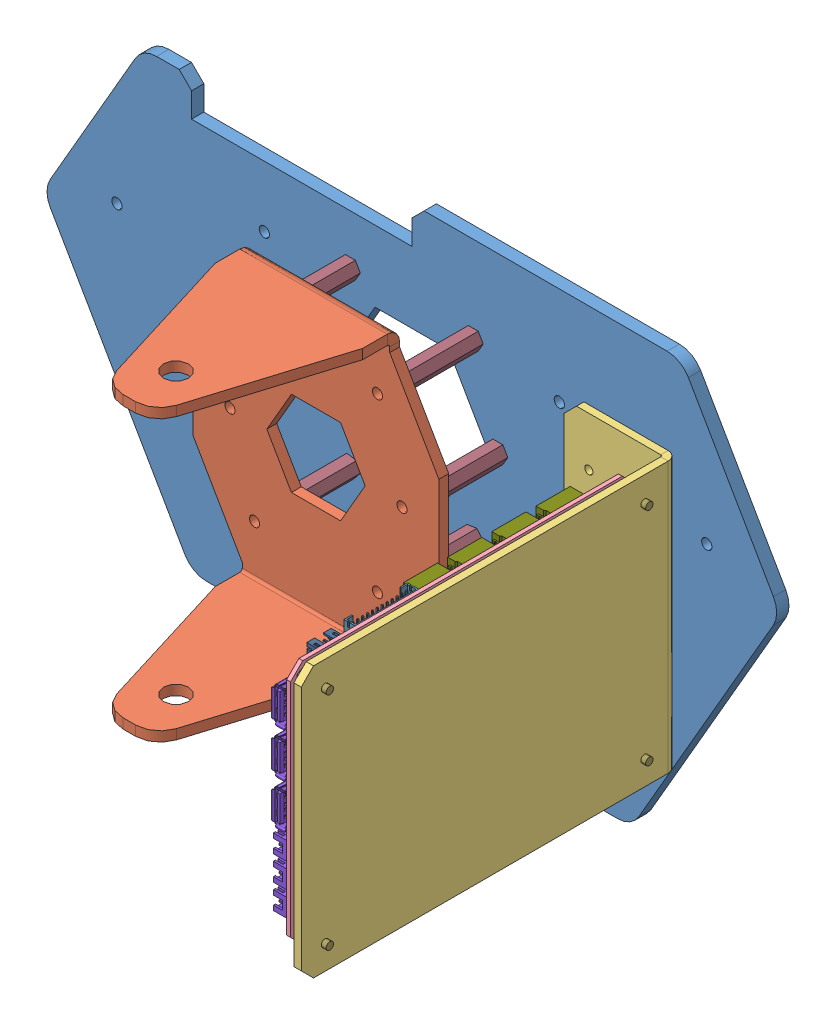
SolidWorks assembly Work Table Assembly, configuration 預設. Lengths in mm.
Overall size (296.91 174.81 163).
95 component instances, 31 part files, 24 mates.
Components (placement in the parent):
- Work Table-1: Work Table [預設] at origin size (296.91 174.81 5)
- Chassis Handle Steel-1: Chassis Handle Steel [Default] at (0 0 41) x (1 0 0) z (0 -1 0) size (100 80 117.92)
- Main Board Mount-1: Main Board Mount [預設] at (105 35.0962 8) x (1 0 0) z (0 -1 0) size (43 153 110)
- Main Board-1: Main Board [預設] at (99 242.1212 -111.1317) x (0 -1 0) z (-1 0 0) size (100 140 20.2)
  - BoardOutline_Main Board-1: BoardOutline_Main Board [預設] at origin size (100 140 1.6)
  - XTAL_ECS-120-32-5P-TR_ECS-120-32-5P-TR_1-1: XTAL_ECS-120-32-5P-TR_ECS-120-32-5P-TR_1 [預設] at (267.025 238.5 1.6) x (0 1 0) z (0 0 1) size (13.2 4.8 4.31)
  - FCI_06-381-2PIN_(180)_2_Pin_1-1: FCI_06-381-2PIN_(180)_2_Pin_1 [預設] at (287.025 139.5 1.6) size (8.81 7.6 12.7)
  - LED_0603_1608_BLUE_LED_1-1: LED_0603_1608_BLUE_LED_1 [預設] at (305 250.5 1.6) size (1.6 0.8 0.53)
  - LED_0603_1608_BLUE_LED_1-2: LED_0603_1608_BLUE_LED_1 [預設] at (305.025 248.5 1.6) size (1.6 0.8 0.53)
  - LED_0603_1608_BLUE_LED_1-3: LED_0603_1608_BLUE_LED_1 [預設] at (305.025 246.5 1.6) size (1.6 0.8 0.53)
  - LED_0603_1608_BLUE_LED_1-4: LED_0603_1608_BLUE_LED_1 [預設] at (305.025 244.5 1.6) size (1.6 0.8 0.53)
  - OST_USB-A1HSW6_USB-A1HSW6_1-1: OST_USB-A1HSW6_USB-A1HSW6_1 [預設] at (229 256.5 1.6) x (-1 0 0) z (0 0 1) size (15.8 14.1 10.8)
  - OST_USB-A1HSW6_USB-A1HSW6_1-2: OST_USB-A1HSW6_USB-A1HSW6_1 [預設] at (247 256.5 1.6) x (-1 0 0) z (0 0 1) size (15.8 14.1 10.8)
  - OST_USB-A1HSW6_USB-A1HSW6_1-3: OST_USB-A1HSW6_USB-A1HSW6_1 [預設] at (265 256.5 1.6) x (-1 0 0) z (0 0 1) size (15.8 14.1 10.8)
  - JST_B3B-PH-K_3_Pin_1-1: JST_B3B-PH-K_3_Pin_1 [預設] at (251 214.5 1.6) size (7.9 4.5 9.4)
  - JST_B3B-PH-K_3_Pin_1-2: JST_B3B-PH-K_3_Pin_1 [預設] at (263 214.5 1.6) size (7.9 4.5 9.4)
  - JST_B3B-PH-K_3_Pin_1-3: JST_B3B-PH-K_3_Pin_1 [預設] at (278.875 207.7 1.6) size (7.9 4.5 9.4)
  - JST_B3B-PH-K_3_Pin_1-4: JST_B3B-PH-K_3_Pin_1 [預設] at (278.875 215.075 1.6) size (7.9 4.5 9.4)
  - JST_B3B-PH-K_3_Pin_1-5: JST_B3B-PH-K_3_Pin_1 [預設] at (253 146.5 1.6) size (7.9 4.5 9.4)
  - JST_B3B-PH-K_3_Pin_1-6: JST_B3B-PH-K_3_Pin_1 [預設] at (238 157.5 1.6) size (7.9 4.5 9.4)
  - JST_B3B-PH-K_3_Pin_1-7: JST_B3B-PH-K_3_Pin_1 [預設] at (253 157.5 1.6) size (7.9 4.5 9.4)
  - JST_B3B-PH-K_3_Pin_1-8: JST_B3B-PH-K_3_Pin_1 [預設] at (245 222.5 1.6) size (7.9 4.5 9.4)
  - JST_B3B-PH-K_3_Pin_1-9: JST_B3B-PH-K_3_Pin_1 [預設] at (257 222.5 1.6) size (7.9 4.5 9.4)
  - JST_B3B-PH-K_3_Pin_1-10: JST_B3B-PH-K_3_Pin_1 [預設] at (238 146.5 1.6) size (7.9 4.5 9.4)
  - JST_B3B-PH-K_3_Pin_1-11: JST_B3B-PH-K_3_Pin_1 [預設] at (226.6878 214.4734 1.6) size (7.9 4.5 9.4)
  - JST_B3B-PH-K_3_Pin_1-12: JST_B3B-PH-K_3_Pin_1 [預設] at (239 214.5 1.6) size (7.9 4.5 9.4)
  - JST_B4B-PH-K_4_Pin_1-1: JST_B4B-PH-K_4_Pin_1 [預設] at (238 195.5 1.6) size (9.9 4.5 9.4)
  - JST_B4B-PH-K_4_Pin_1-2: JST_B4B-PH-K_4_Pin_1 [預設] at (251 195.5 1.6) size (9.9 4.5 9.4)
  - JST_B4B-PH-K_4_Pin_1-3: JST_B4B-PH-K_4_Pin_1 [預設] at (245 166.5 1.6) size (9.9 4.5 9.4)
  - JST_B4B-PH-K_4_Pin_1-4: JST_B4B-PH-K_4_Pin_1 [預設] at (215.725 245.3 1.6) x (0 1 0) z (0 0 1) size (9.9 4.5 9.4)
  - JST_XH_B6B-XH-A_6_Pin_1-1: JST_XH_B6B-XH-A_6_Pin_1 [預設] at (245 175.5 1.6) size (17.4 5.75 10.4)
  - JST_XH_B6B-XH-A_6_Pin_1-2: JST_XH_B6B-XH-A_6_Pin_1 [預設] at (245 186.5 1.6) size (17.4 5.75 10.4)
  - RES_0603_1608_RF_Resistor_1-1: RES_0603_1608_RF_Resistor_1 [預設] at (301 250.5 1.6) x (-1 0 0) z (0 0 1) size (1.6 0.8 0.45)
  - RES_0603_1608_RF_Resistor_1-2: RES_0603_1608_RF_Resistor_1 [預設] at (249.525 239.5 1.6) x (0 1 0) z (0 0 1) size (1.6 0.8 0.45)
  - RES_0603_1608_RF_Resistor_1-3: RES_0603_1608_RF_Resistor_1 [預設] at (225.85 227.775 1.6) size (1.6 0.8 0.45)
  - RES_0603_1608_RF_Resistor_1-4: RES_0603_1608_RF_Resistor_1 [預設] at (232.15 227.8 1.6) size (1.6 0.8 0.45)
  - RES_0603_1608_RF_Resistor_1-5: RES_0603_1608_RF_Resistor_1 [預設] at (233.725 235.15 1.6) x (0 1 0) z (0 0 1) size (1.6 0.8 0.45)
  - RES_0603_1608_RF_Resistor_1-6: RES_0603_1608_RF_Resistor_1 [預設] at (223.725 235.15 1.6) x (0 1 0) z (0 0 1) size (1.6 0.8 0.45)
  - RES_0603_1608_RF_Resistor_1-7: RES_0603_1608_RF_Resistor_1 [預設] at (238.225 231.65 1.6) x (0 -1 0) z (0 0 1) size (1.6 0.8 0.45)
  - RES_0603_1608_RF_Resistor_1-8: RES_0603_1608_RF_Resistor_1 [預設] at (228.225 231.65 1.6) x (0 -1 0) z (0 0 1) size (1.6 0.8 0.45)
  - RES_0603_1608_RF_Resistor_1-9: RES_0603_1608_RF_Resistor_1 [預設] at (285.25 230.45 1.6) size (1.6 0.8 0.45)
  - RES_0603_1608_RF_Resistor_1-10: RES_0603_1608_RF_Resistor_1 [預設] at (273.85 240.125 1.6) x (0 1 0) z (0 0 1) size (1.6 0.8 0.45)
  - RES_0603_1608_RF_Resistor_1-11: RES_0603_1608_RF_Resistor_1 [預設] at (282.025 230.95 1.6) x (0 1 0) z (0 0 1) size (1.6 0.8 0.45)
  - RES_0603_1608_RF_Resistor_1-12: RES_0603_1608_RF_Resistor_1 [預設] at (301.025 244.5 1.6) x (-1 0 0) z (0 0 1) size (1.6 0.8 0.45)
  - RES_0603_1608_RF_Resistor_1-13: RES_0603_1608_RF_Resistor_1 [預設] at (301.025 248.5 1.6) x (-1 0 0) z (0 0 1) size (1.6 0.8 0.45)
  - RES_0603_1608_RF_Resistor_1-14: RES_0603_1608_RF_Resistor_1 [預設] at (301.025 246.5 1.6) x (-1 0 0) z (0 0 1) size (1.6 0.8 0.45)
  - SOT-23-3_SINGLE_N-MOSFET_1-1: SOT-23-3_SINGLE_N-MOSFET_1 [預設] at (234.725 231.65 1.6) x (0 1 0) z (0 0 1) size (3.01 2.84 1.18)
  - SOT-23-3_SINGLE_N-MOSFET_1-2: SOT-23-3_SINGLE_N-MOSFET_1 [預設] at (224.725 231.65 1.6) x (0 1 0) z (0 0 1) size (3.01 2.84 1.18)
  - SOT-23-3_SINGLE_N-MOSFET_1-3: SOT-23-3_SINGLE_N-MOSFET_1 [預設] at (274.025 244.5 1.6) size (3.01 2.84 1.18)
  - JST_S12B-PH-K_12_Pin_1-1: JST_S12B-PH-K_12_Pin_1 [預設] at (218.5 223.45 1.6) x (0 1 0) z (0 0 1) size (25.9 7.6 8.2)
  - MYRIO_MXP_PORT_VERTICAL_2x17_Pin_1-1: MYRIO_MXP_PORT_VERTICAL_2x17_Pin_1 [預設] at (303.025 161.5 1.6) x (0 -1 0) z (0 0 1) size (50.84 9.1 12.1)
  - MYRIO_MXP_PORT_VERTICAL_2x17_Pin_1-2: MYRIO_MXP_PORT_VERTICAL_2x17_Pin_1 [預設] at (303.025 215.5 1.6) x (0 -1 0) z (0 0 1) size (50.84 9.1 12.1)
  - XT30PB(2+2)_XT30(2+2)_1-1: XT30PB(2+2)_XT30(2+2)_1 [預設] at (218 163.5 1.6) x (0 1 0) z (0 0 1) size (15.5 5.2 11.3)
  - XT30PB(2+2)_XT30(2+2)_1-2: XT30PB(2+2)_XT30(2+2)_1 [預設] at (218 145.5 1.6) x (0 1 0) z (0 0 1) size (15.5 5.2 11.3)
  - XT30PB(2+2)_XT30(2+2)_1-3: XT30PB(2+2)_XT30(2+2)_1 [預設] at (218 199.5 1.6) x (0 1 0) z (0 0 1) size (15.5 5.2 11.3)
  - XT30PB(2+2)_XT30(2+2)_1-4: XT30PB(2+2)_XT30(2+2)_1 [預設] at (218 181.5 1.6) x (0 1 0) z (0 0 1) size (15.5 5.2 11.3)
  - JST_B2B-PH-K_2_Pin_1-1: JST_B2B-PH-K_2_Pin_1 [預設] at (235.725 240.15 1.6) size (5.9 4.5 9.4)
  - JST_B2B-PH-K_2_Pin_1-2: JST_B2B-PH-K_2_Pin_1 [預設] at (225.725 240.15 1.6) size (5.9 4.5 9.4)
  - JST_B2B-PH-K_2_Pin_1-3: JST_B2B-PH-K_2_Pin_1 [預設] at (235 222.5 1.6) size (5.9 4.5 9.4)
  - JST_B2B-PH-K_2_Pin_1-4: JST_B2B-PH-K_2_Pin_1 [預設] at (226 222.5 1.6) size (5.9 4.5 9.4)
  - SOP64P600X175-28N_FE1.1S_1-1: SOP64P600X175-28N_FE1.1S_1 [預設] at (257.025 239.5 1.6) x (0 -1 0) z (0 0 1) size (6 9.9 1.75)
  - SOT95P280X145-5N_SN74AHC1G04DBVR_1-1: SOT95P280X145-5N_SN74AHC1G04DBVR_1 [預設] at (276.75 232.975 1.6) size (2.43 2.79 1.09)
  - MP1584EN_DC-DC_Component_1_1-1: MP1584EN_DC-DC_Component_1_1 [預設] at (272.025 195.5 1.6) x (-1 0 0) z (0 0 1) size (20.4 15.4 3.6)
  - MP1584EN_DC-DC_Component_1_1-2: MP1584EN_DC-DC_Component_1_1 [預設] at (272.025 175.5 1.6) x (-1 0 0) z (0 0 1) size (20.4 15.4 3.6)
  - MP1584EN_DC-DC_Component_1_1-3: MP1584EN_DC-DC_Component_1_1 [預設] at (272.025 155.5 1.6) x (-1 0 0) z (0 0 1) size (20.4 15.4 3.6)
  - CAP_0603_1608_RF_Capacitor_1-1: CAP_0603_1608_RF_Capacitor_1 [預設] at (260.5 231.45 1.6) x (0 1 0) z (0 0 1) size (1.6 0.82 0.82)
  - CAP_0603_1608_RF_Capacitor_1-2: CAP_0603_1608_RF_Capacitor_1 [預設] at (254.075 231.55 1.6) x (0 1 0) z (0 0 1) size (1.6 0.82 0.82)
  - CAP_0603_1608_RF_Capacitor_1-3: CAP_0603_1608_RF_Capacitor_1 [預設] at (257.025 231.5 1.6) x (0 1 0) z (0 0 1) size (1.6 0.82 0.82)
  - CAP_1206_3216_-_1.8MM_Capacitor_1-1: CAP_1206_3216_-_1.8MM_Capacitor_1 [預設] at (242.1 231.8 1.6) x (0 -1 0) z (0 0 1) size (3.2 1.6 1.8)
  - CAP_1206_3216_-_1.8MM_Capacitor_1-2: CAP_1206_3216_-_1.8MM_Capacitor_1 [預設] at (250.425 231.675 1.6) x (0 -1 0) z (0 0 1) size (3.2 1.6 1.8)
  - CAP_1206_3216_-_1.8MM_Capacitor_1-3: CAP_1206_3216_-_1.8MM_Capacitor_1 [預設] at (246.4 231.75 1.6) x (0 -1 0) z (0 0 1) size (3.2 1.6 1.8)
  - CAP_AL_TH_D10_L5_H14.5_Polarised_Capacitor_1-1: CAP_AL_TH_D10_L5_H14.5_Polarised_Capacitor_1 [預設] at (268.025 137.5 1.6) size (10 10 17.7)
  - CAP_POL_2917_7343_Polarised_Capacitor_1-1: CAP_POL_2917_7343_Polarised_Capacitor_1 [預設] at (290.025 175.5 1.6) x (0 1 0) z (0 0 1) size (7.3 4.3 4.1)
  - CAP_POL_2917_7343_Polarised_Capacitor_1-2: CAP_POL_2917_7343_Polarised_Capacitor_1 [預設] at (290.025 195.5 1.6) x (0 1 0) z (0 0 1) size (7.3 4.3 4.1)
  - CAP_POL_2917_7343_Polarised_Capacitor_1-3: CAP_POL_2917_7343_Polarised_Capacitor_1 [預設] at (290.025 155.5 1.6) x (0 1 0) z (0 0 1) size (7.3 4.3 4.1)
  - BZ_ZK-1205S_Buzzer_1-1: BZ_ZK-1205S_Buzzer_1 [預設] at (284.525 244.5 1.6) size (12 12 15)
  - JST_XH_B2B-XH-A_2_Pin_1-1: JST_XH_B2B-XH-A_2_Pin_1 [預設] at (299 260.5 1.6) size (7.4 5.75 10.4)
  - JST_XH_B2B-XH-A_2_Pin_1-2: JST_XH_B2B-XH-A_2_Pin_1 [預設] at (289 260.5 1.6) size (7.4 5.75 10.4)
  - JST_XH_B2B-XH-A_2_Pin_1-3: JST_XH_B2B-XH-A_2_Pin_1 [預設] at (279 260.5 1.6) size (7.4 5.75 10.4)
  - SOIC127P600X175-14N_SN74HC126DG4_1-1: SOIC127P600X175-14N_SN74HC126DG4_1 [預設] at (281.9 224.35 1.6) size (6 8.65 1.75)
  - JST_XH_B4B-XH-A_4_Pin_1-1: JST_XH_B4B-XH-A_4_Pin_1 [預設] at (226 147.5 1.6) x (0 1 0) z (0 0 1) size (12.4 5.75 10.4)
  - JST_XH_B4B-XH-A_4_Pin_1-2: JST_XH_B4B-XH-A_4_Pin_1 [預設] at (226 165.5 1.6) x (0 1 0) z (0 0 1) size (12.4 5.75 10.4)
  - JST_XH_B4B-XH-A_4_Pin_1-3: JST_XH_B4B-XH-A_4_Pin_1 [預設] at (226 183.5 1.6) x (0 1 0) z (0 0 1) size (12.4 5.75 10.4)
  - JST_XH_B4B-XH-A_4_Pin_1-4: JST_XH_B4B-XH-A_4_Pin_1 [預設] at (226 201.5 1.6) x (0 1 0) z (0 0 1) size (12.4 5.75 10.4)
  - JST_XH_B7B-XH-90_7_Pin_1-1: JST_XH_B7B-XH-90_7_Pin_1 [預設] at (252 205.5 1.6) x (-1 0 0) z (0 0 1) size (19.9 5.75 10.4)
- M3x6+5-1: M3x6+5 [預設] at (99 25.0962 148.3683) x (0 0.5 -0.866025) z (1 0 0) size (5.26 4.56 11)
- M3x6+5-2: M3x6+5 [預設] at (99 25.0962 18.3683) x (0 0.5 -0.866025) z (1 0 0) size (5.26 4.56 11)
- M3x6+5-3: M3x6+5 [預設] at (99 -64.9038 148.3683) x (0 0.5 -0.866025) z (1 0 0) size (5.26 4.56 11)
- M3x6+5-4: M3x6+5 [預設] at (99 -64.9038 18.3683) x (0 0.5 -0.866025) z (1 0 0) size (5.26 4.56 11)
- M4x35mm_toothed -8: M4x35mm_toothed  [預設] at (25 35 5) x (0.5 -0.866025 0) z (0 0 1) size (8.08 7 45)
- M4x35mm_toothed -9: M4x35mm_toothed  [預設] at (35 0 5) x (0.5 -0.866025 0) z (0 0 1) size (8.08 7 45)
- M4x35mm_toothed -10: M4x35mm_toothed  [預設] at (25 -35 5) x (0.623859 -0.781537 0) z (0 0 1) size (8.08 7 45)
- M4x35mm_toothed -11: M4x35mm_toothed  [預設] at (-25 -35 5) x (0.623859 0.781537 0) z (0 0 1) size (8.08 7 45)
- M4x35mm_toothed -12: M4x35mm_toothed  [預設] at (-35 0 5) x (0.5 0.866025 0) z (0 0 1) size (8.08 7 45)
- M4x35mm_toothed -13: M4x35mm_toothed  [預設] at (-25 35 5) x (0.5 0.866025 0) z (0 0 1) size (8.08 7 45)
Mates (geometry in assembly coordinates):
- 同軸心1: concentric aligned: cylinder of Work Table-1 through (34.641 20 5) axis (0 0 1) radius 1.65; cylinder of M4x35mm_toothed -1 through (34.641 20 -5) axis (0 0 1) radius 2
- 重合/共線/共點1: coincident anti-aligned: plane of Work Table-1 through (0 0 5) normal (0 0 1); plane of M4x35mm_toothed -1 through (34.641 20 5) normal (0 0 -1)
- 平行1: parallel aligned: plane of Work Table-1 through (30 -104.9038 455.6039) normal (0 -1 0); plane of M4x35mm_toothed -1 through (32.6203 16.5 40) normal (0 -1 0)
- 重合/共線/共點2: coordinate: point of Work Table-1
- 同軸心3: concentric aligned: circle of M4x35mm_toothed -7; cylinder of Chassis Handle Steel-1 through (-34.641 -20 39.999) axis (0 0 1) radius 2.1
- 重合/共線/共點3: coincident: line of M4x35mm_toothed -7 through (-36.6617 -16.5 40) axis (-0.5 -0.866025 0); plane of Chassis Handle Steel-1 through (0 0 40) normal (0 0 -1)
- 同軸心4: concentric aligned: cylinder of Work Table-1 through (75 15.0962 5) axis (0 0 1) radius 1.25; cylinder of Main Board Mount-1 through (75 15.0962 4.999) axis (0 0 1) radius 1.65
- 同軸心5: concentric aligned: cylinder of Work Table-1 through (75 -54.9038 5) axis (0 0 1) radius 1.25; cylinder of Main Board Mount-1 through (75 -54.9038 4.999) axis (0 0 1) radius 1.65
- 平行2: parallel anti-aligned: plane of Work Table-1 through (0 0 5) normal (0 0 1); plane of Main Board Mount-1 through (65 -74.9038 5) normal (0 0 -1)
- 重合/共線/共點4: coincident anti-aligned: plane of Work Table-1 through (0 0 5) normal (0 0 1); plane of Main Board Mount-1 through (65 -74.9038 5) normal (0 0 -1)
- 同軸心6: concentric aligned: cylinder of Main Board Mount-1 through (105 25.0962 148.3683) axis (-1 0 0) radius 1.25; cylinder of M3x6+5-1 through (110 25.0962 148.3683) axis (-1 0 0) radius 1.5
- 重合/共線/共點5: coincident anti-aligned: plane of Main Board Mount-1 through (105 -74.9038 8) normal (-1 0 0); plane of M3x6+5-1 through (105 25.0962 148.3683) normal (1 0 0)
- 平行3: parallel aligned: plane of Main Board Mount-1 through (105 -74.9038 158) normal (0 0 1); plane of M3x6+5-1 through (105 26.4112 150.6459) normal (0 0 1)
- 重合/共線/共點6: coincident anti-aligned: plane of Main Board-1/BoardOutline_Main Board-1 through (99 242.1212 -111.1317) normal (1 0 0); plane of M3x6+5-1 through (99 25.0962 148.3683) normal (-1 0 0)
- 同軸心7: concentric anti-aligned: cylinder of Main Board-1/BoardOutline_Main Board-1 through (99 -64.9038 148.3683) axis (1 0 0) radius 1.65; cylinder of M3x6+5-3 through (99 -64.9038 148.3683) axis (-1 0 0) radius 1.25
- 同軸心8: concentric anti-aligned: cylinder of Main Board-1/BoardOutline_Main Board-1 through (99 25.0962 148.3683) axis (1 0 0) radius 1.65; cylinder of M3x6+5-1 through (99 25.0962 148.3683) axis (-1 0 0) radius 1.25
- 同軸心9: concentric aligned: cylinder of Work Table-1 through (25 35 5) axis (0 0 1) radius 1.65; cylinder of M4x35mm_toothed -8 through (25 35 -5) axis (0 0 1) radius 2
- 重合/共線/共點7: coincident anti-aligned: plane of Work Table-1 through (0 0 5) normal (0 0 1); plane of M4x35mm_toothed -8 through (25 35 5) normal (0 0 -1)
- 平行4: parallel aligned: plane of Work Table-1 through (0 69.9038 507.3677) normal (0 1 0); plane of M4x35mm_toothed -8 through (27.0207 38.5 40) normal (0 1 0)
- 同軸心10: concentric aligned: cylinder of Work Table-1 through (35 0 5) axis (0 0 1) radius 1.65; cylinder of M4x35mm_toothed -9 through (35 0 -5) axis (0 0 1) radius 2
- 重合/共線/共點8: coincident: plane of Work Table-1 through (0 0 5) normal (0 0 1); line of M4x35mm_toothed -9 through (32.9793 -3.5 5) axis (1 0 0)
- 平行5: parallel aligned: plane of Work Table-1 through (30 -104.9038 455.6039) normal (0 -1 0); plane of M4x35mm_toothed -9 through (32.9793 -3.5 40) normal (0 -1 0)
- 同軸心11: concentric aligned: cylinder of Work Table-1 through (25 -35 5) axis (0 0 1) radius 1.65; cylinder of M4x35mm_toothed -10 through (25 -35 -5) axis (0 0 1) radius 2
- 重合/共線/共點9: coincident: plane of Work Table-1 through (0 0 5) normal (0 0 1); line of M4x35mm_toothed -10 through (23.5253 -38.7628 5) axis (0.98876 0.14951 0)
